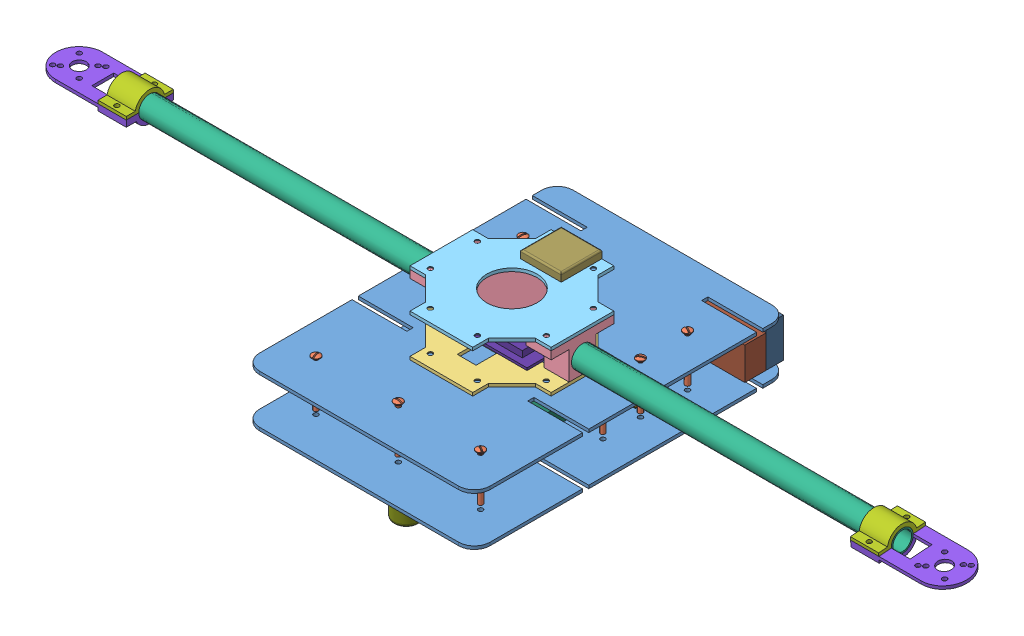
SolidWorks assembly montagem_chapa_eletronica, configuration Valor predeterminado. Lengths in mm.
Overall size (582 101.5 204.05).
32 component instances, 17 part files, 19 mates.
Components (placement in the parent):
- chapa_montagem-1: chapa_montagem [Valor predeterminado] at (19.8562 -214.5 9.865) x (1 0 0) z (0 1 0) size (147 200 36.45)
  - chapa-1: chapa [Valor predeterminado] at (-18.1566 10.6922 199) size (147 200 2)
  - countersunk slotted raised head screw_iso-1: countersunk slotted raised head screw_iso [ISO 2010 - M3 x 30 --- 30N] at (-70.6566 -64.3078 203.3736) x (0 0 -1) z (-0.244417 0.96967 0) size (30.69 5.5 5.44)
  - countersunk slotted raised head screw_iso-2: countersunk slotted raised head screw_iso [ISO 2010 - M3 x 30 --- 30N] at (34.3434 -64.3078 204.0583) x (0 0 -1) z (-0.882458 0.470391 0) size (30.69 5.5 5.44)
  - countersunk slotted raised head screw_iso-3: countersunk slotted raised head screw_iso [ISO 2010 - M3 x 30 --- 30N] at (34.3434 13.6922 204.2375) x (0 0 -1) z (0.649404 -0.760444 0) size (30.69 5.5 5.44)
  - countersunk slotted raised head screw_iso-4: countersunk slotted raised head screw_iso [ISO 2010 - M3 x 30 --- 30N] at (34.3434 37.6922 203.655) x (0 0 -1) z (0.871892 0.489698 0) size (30.69 5.5 5.44)
  - countersunk slotted raised head screw_iso-5: countersunk slotted raised head screw_iso [ISO 2010 - M3 x 30 --- 30N] at (34.3434 67.6922 203.8907) x (0 0 -1) z (0.898776 -0.438408 0) size (30.69 5.5 5.44)
  - countersunk slotted raised head screw_iso-6: countersunk slotted raised head screw_iso [ISO 2010 - M3 x 30 --- 30N] at (-70.6566 67.6922 203.4844) x (0 0 -1) z (-0.167696 -0.985839 0) size (30.69 5.5 5.44)
  - countersunk slotted raised head screw_iso-7: countersunk slotted raised head screw_iso [ISO 2010 - M3 x 30 --- 30N] at (-70.6566 37.6922 204.0291) x (0 0 -1) z (0.961696 -0.274118 0) size (30.69 5.5 5.44)
  - countersunk slotted raised head screw_iso-8: countersunk slotted raised head screw_iso [ISO 2010 - M3 x 30 --- 30N] at (-70.6566 13.6922 203.5823) x (0 0 -1) z (-0.828055 0.560647 0) size (30.69 5.5 5.44)
  - countersunk slotted raised head screw_iso-9: countersunk slotted raised head screw_iso [ISO 2010 - M3 x 30 --- 30N] at (-18.1566 -64.3078 204.4619) x (0 0 -1) z (-0.994832 0.101533 0) size (30.69 5.5 5.44)
  - chapa-2: chapa [Valor predeterminado] at (-18.1566 10.6922 168) size (147 200 2)
- helice_montagem-5: helice_montagem [Valor predeterminado] at (6.0329 -9.7641 -90) size (582 27 90)
  - centro_helice_2-1: centro_helice_2 [Valor predeterminado] at (-6.0329 -3.7359 90) size (90 2 90)
  - suporte_haste-1: suporte_haste [Valor predeterminado] at (22.9671 8.2641 90) x (0 0 -1) z (1 0 0) size (40 23 16)
  - centro_helice_1-1: centro_helice_1 [Valor predeterminado] at (-6.0329 21.2641 90) size (90 2 90)
  - suporte_haste-2: suporte_haste [Valor predeterminado] at (-51.0329 8.2641 90) x (0 0 -1) z (1 0 0) size (40 23 16)
  - helice_haste-1: helice_haste [Valor predeterminado] at (242.9671 8.2641 90) x (0 -0.998136 -0.061023) z (-1 0 0) size (14 14 220)
  - helice_haste-3: helice_haste [Valor predeterminado] at (-35.0329 8.2641 90) x (0 -0.416607 -0.909087) z (-1 0 0) size (14 14 220)
  - suporte_helice_2-1: suporte_helice_2 [Valor predeterminado] at (224.9671 8.2087 90.7981) x (0 0.069251 -0.997599) z (1 0 0) size (30 9.5 18)
  - suporte_helice-1: suporte_helice [Valor predeterminado] at (254.9671 8.2641 90) x (-1 0 0) z (0 -0.069251 0.997599) size (60 9.5 30)
  - suporte_helice-2: suporte_helice [Valor predeterminado] at (-267.0329 8.2641 90) x (1 0 0) z (0 0 -1) size (60 9.5 30)
- Beagle-1: Beagle [Default] at (5.4034 -39.0748 -50.1572) x (0 0 -1) z (1 0 0) size (54.61 18.55 88.98)
- 5v5a_converter-1: 5v5a_converter [Valor predeterminado] at (14.3103 -19.5 -104.8801) size (54 25 11)
- 9v_45a_converter-2: 9v_45a_converter [Valor predeterminado] at (30.3103 -44.5 -93.8801) x (0 1 0) z (0 0 1) size (20.7 38 13.6)
- gps_antenna-1: gps_antenna [Valor predeterminado] at (23.1568 18.5 -18.0087) x (1 0 0) z (0 -1 0) size (26 26 5)
- gps_base-1: gps_base [Valor predeterminado] at (-11.0924 11.5 1.8944) x (1 0 0) z (0 -1 0) size (37 37 4)
- rx-1: rx [Valor predeterminado] at (-53.0747 -44.5 -90.0558) x (-1 0 0) z (0 1 0) size (40 20 15)
- cortex m4-1: cortex m4 [Predeterminada] at (0.5226 -44.5 39.9179) size (76 10 90)
- sonar-1: sonar [Predeterminada] at (-3.3907 -67.5 62.4011) x (-1 0 0) z (0 0 1) size (20 36.5 22)
- imu-1: imu [Predeterminada] at (0.9221 -11.5 -3.8953) size (53 5.5 35)
- suporte_helice_2-1: suporte_helice_2 [Valor predeterminado] at (-249 -1.5 0.8) x (0 0 -1) z (1 0 0) size (30 9.5 18)
Mates (geometry in assembly coordinates):
- Coincidente38: coordinate: point of helice_montagem-5; point of assembly
- Coincidente39: coincident anti-aligned: plane of chapa_montagem-1/chapa-1 through (-61.8004 -13.5 -90.8272) normal (0 1 0); plane of helice_montagem-5/centro_helice_2-1 through (0 -13.5 0) normal (0 -1 0)
- Paralelo3: parallel aligned: line of chapa_montagem-1/chapa-1 through (-61.8004 -15.5 99.1728) axis (1 0 0); line of helice_montagem-5/centro_helice_1-1 through (-20 11.5 45) axis (1 0 0)
- Distância1: distance = 7 mm aligned: plane of Beagle-1 through (42.2334 -37.5 -71.1122) normal (0 1 0); plane of chapa_montagem-1/chapa-2 through (-61.8004 -44.5 -90.8272) normal (0 1 0)
- Coincidente5652: coincident anti-aligned: plane of helice_montagem-5/centro_helice_1-1 through (0 13.5 0) normal (0 1 0); plane of gps_antenna-1 through (23.1568 13.5 -18.0087) normal (0 -1 0)
- Coincidente5653: coincident anti-aligned: plane of helice_montagem-5/centro_helice_1-1 through (0 11.5 0) normal (0 -1 0); plane of gps_base-1 through (-11.0924 11.5 1.8944) normal (0 1 0)
- Coincidente5663: coincident aligned: plane of 5v5a_converter-1 through (14.3103 -44.5 -93.8801) normal (0 -1 0); plane of 9v_45a_converter-2 through (30.3103 -44.5 -80.2801) normal (0 -1 0)
- Coincidente5664: coincident aligned: plane of 5v5a_converter-1 through (68.3103 -19.5 -93.8801) normal (1 0 0); plane of 9v_45a_converter-2 through (68.3103 -44.5 -80.2801) normal (1 0 0)
- Coincidente5666: coincident anti-aligned: plane of chapa_montagem-1/chapa-2 through (-61.8004 -44.5 -90.8272) normal (0 1 0); plane of 9v_45a_converter-2 through (30.3103 -44.5 -80.2801) normal (0 -1 0)
- Coincidente5668: coincident anti-aligned: plane of 5v5a_converter-1 through (14.3103 -19.5 -93.8801) normal (0 0 1); plane of 9v_45a_converter-2 through (30.3103 -44.5 -93.8801) normal (0 0 -1)
- Distância2: distance = 24 mm aligned: plane of Beagle-1 through (51.1996 -24.85 -25.707) normal (1 0 0); plane of chapa_montagem-1/chapa-2 through (75.1996 -44.5 26.1728) normal (1 0 0)
- Distância3: distance = 24 mm aligned: plane of Beagle-1 through (30.1684 -29 -76.8272) normal (0 0 -1); plane of chapa_montagem-1/chapa-2 through (-61.8004 -44.5 -100.8272) normal (0 0 -1)
- Coincidente5673: coincident anti-aligned: plane of chapa_montagem-1/chapa-2 through (-61.8004 -44.5 -90.8272) normal (0 1 0); plane of rx-1 through (-53.0747 -44.5 -90.0558) normal (0 -1 0)
- Coincidente5675: coincident aligned: plane of chapa_montagem-1/chapa-2 through (-71.8004 -44.5 -84.8272) normal (-1 0 0); plane of rx-1 through (-71.8004 -34.5 -79.389) normal (-1 0 0)
- Coincidente5676: coincident anti-aligned: plane of chapa_montagem-1/chapa-2 through (-61.8004 -44.5 -90.8272) normal (0 1 0); plane of cortex m4-1 through (0.5226 -44.5 39.9179) normal (0 -1 0)
- Coincidente5677: coincident anti-aligned: plane of chapa_montagem-1/chapa-2 through (-61.8004 -46.5 -90.8272) normal (0 -1 0); plane of sonar-1 through (-9.87 -46.5 57.1768) normal (0 1 0)
- Coincidente5679: coincident anti-aligned: plane of helice_montagem-5/centro_helice_2-1 through (0 -11.5 0) normal (0 1 0); plane of imu-1 through (0.9221 -11.5 -3.8953) normal (0 -1 0)
- Concêntrico1: concentric anti-aligned: cylinder of helice_montagem-5/helice_haste-3 through (-249 -1.5 0) axis (1 0 0) radius 7; cylinder of suporte_helice_2-1 through (-231 -1.5 0) axis (-1 0 0) radius 7
- Concêntrico2: concentric anti-aligned: cylinder of helice_montagem-5/suporte_helice-2 through (-240 11.5 12) axis (0 -1 0) radius 1.5; cylinder of suporte_helice_2-1 through (-240 -16.5 12) axis (0 1 0) radius 1.5
